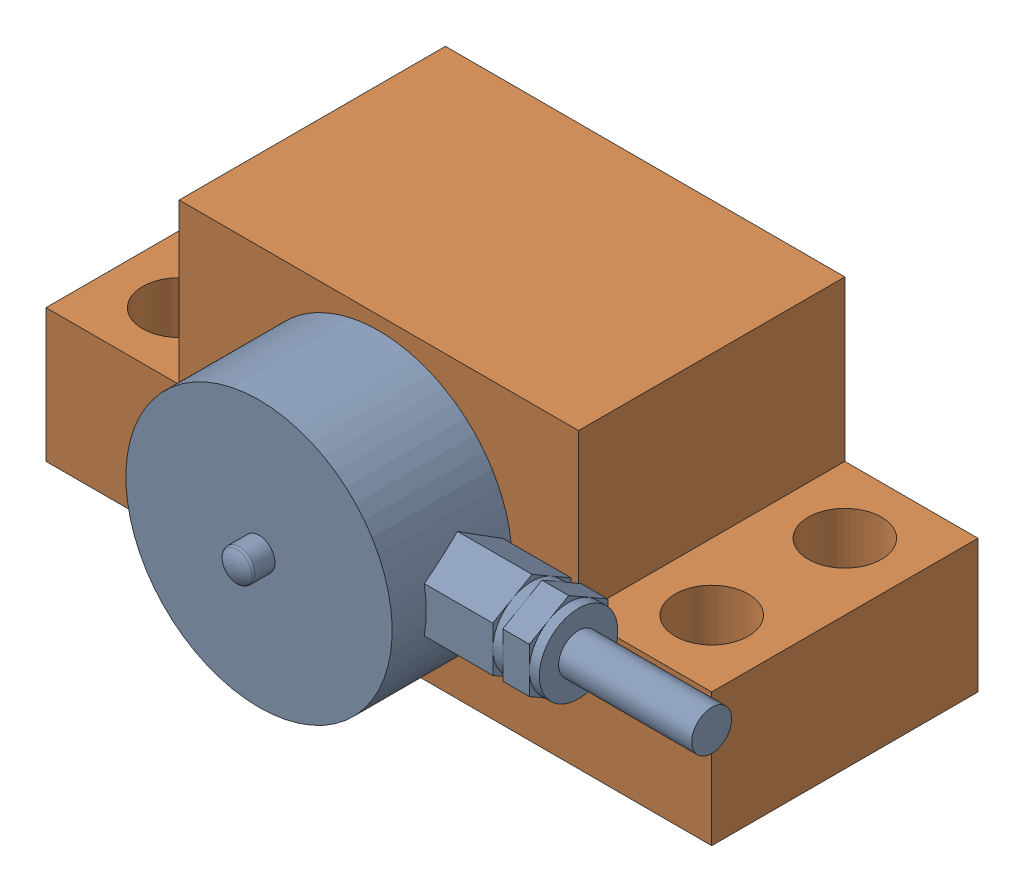
SolidWorks assembly loadcel yatay montaj-1, configuration Default. Lengths in mm.
Overall size (53.5 22 31).
2 component instances, 2 part files, 0 mates.
Components (placement in the parent):
- Mini_Loadcell-1: Mini_Loadcell [Default] at (0 11 19) x (-1 0 0) z (0 1 0) size (38.5 12 20)
- Loadcell yatay ayak-1: Loadcell yatay ayak [Default] at origin size (50 22 20)
